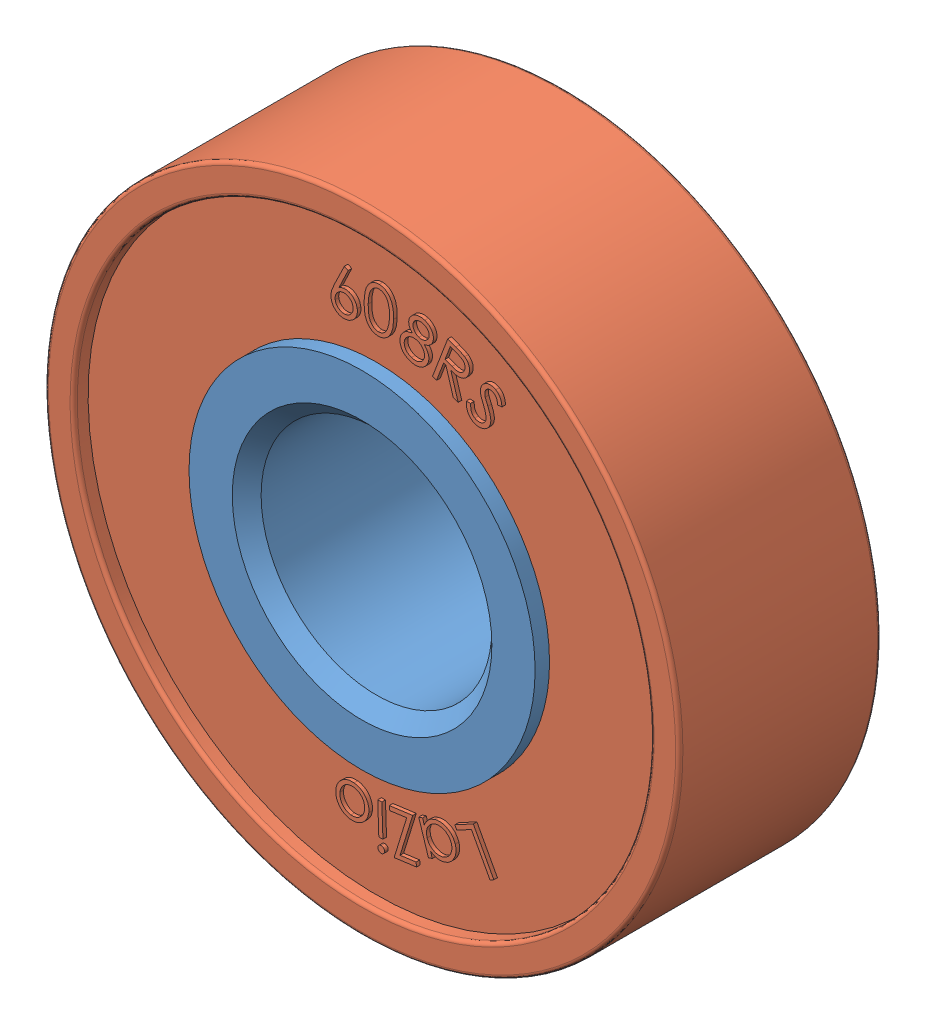
SolidWorks assembly Bearing__Type-1, configuration Default. Lengths in mm.
Overall size (25.78 25.78 7).
2 component instances, 2 part files, 2 mates.
Components (placement in the parent):
- Bearing__Type-1__Inner-1: Bearing__Type-1__Inner [Default] at (6.0462 6.0629 8.5196) size (12 12 7)
- Bearing__Type-1__Outer-1: Bearing__Type-1__Outer [Default] at (6.0462 6.0629 8.5196) x (0 0 1) z (0.190147 0.981756 0) size (7 22 22)
Mates (geometry in assembly coordinates):
- Concentric1: concentric aligned: cylinder of Bearing__Inner__Ring-1 through (6.0462 6.0629 12.0196) axis (0 0 -1) radius 6; cylinder of Bearing__Outer__Ring-1 through (6.0462 6.0629 11.5196) axis (0 0 -1) radius 6
- Coincident1: coincident aligned: plane of Bearing__Inner__Ring-1 through (6.0462 6.0629 12.0196) normal (0 0 1); plane of Bearing__Outer__Ring-1 through (6.0462 6.0629 12.0196) normal (0 0 1)
